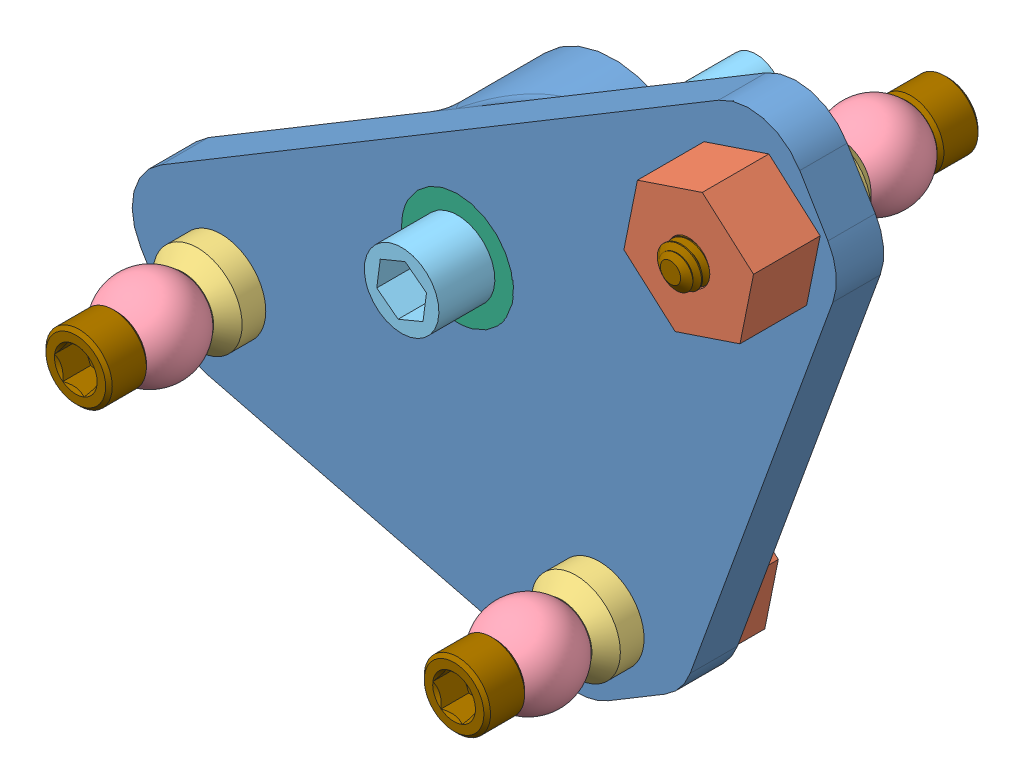
SolidWorks assembly Bell_Crank_Asm, configuration Default. Lengths in mm.
Overall size (48.74 42.1 23.91).
18 component instances, 9 part files, 34 mates.
Components (placement in the parent):
- Bell_Crank-1: Bell_Crank [Default] at (6.8967 -52.6546 -14.6326) x (-0.857289 -0.514836 0) z (0 0 -1) size (42.81 23.4 12.06)
- 2-56_Lock_Nut_MC-91831A002-1: 2-56_Lock_Nut_MC-91831A002 [Default] at (42.2907 -3.3681 -14.6326) size (6.95 7.19 3.57)
- 2-56_Lock_Nut_MC-91831A002-2: 2-56_Lock_Nut_MC-91831A002 [Default] at (33.9367 -25.6257 -20.7444) size (6.95 7.19 3.57)
- 2-56_Lock_Nut_MC-91831A002-3: 2-56_Lock_Nut_MC-91831A002 [Default] at (13.6564 -20.5642 -20.7444) size (6.95 7.19 3.57)
- 2-56_Ball_Joint_Base-1: 2-56_Ball_Joint_Base [Default] at (33.9367 -25.6257 -14.6326) x (-1 0 0) z (0 0 1) size (4.78 4.78 2.03)
- 2-56_Ball_Joint_Base-2: 2-56_Ball_Joint_Base [Default] at (13.6564 -20.5642 -14.6326) x (-1 0 0) z (0 0 1) size (4.78 4.78 2.03)
- 2-56_Ball_Joint_Half_Sphere-1: 2-56_Ball_Joint_Half_Sphere [Default] at (33.9367 -25.6257 -10.8099) x (0.923728 0.383049 0) z (0.383049 -0.923728 0) size (4.78 3.58 4.78)
- 2-56_Ball_Joint_Half_Sphere-2: 2-56_Ball_Joint_Half_Sphere [Default] at (13.6564 -20.5642 -10.8099) x (0.923728 0.383049 0) z (0.383049 -0.923728 0) size (4.78 3.58 4.78)
- 2-56_Ball_Joint_Base-3: 2-56_Ball_Joint_Base [Default] at (42.2907 -3.3681 -17.1726) x (-0.923728 -0.383049 0) z (0 0 -1) size (4.78 4.78 2.03)
- 2-56_Ball_Joint_Half_Sphere-3: 2-56_Ball_Joint_Half_Sphere [Default] at (42.2907 -3.3681 -20.9953) x (-0.049233 0.998787 0) z (-0.998787 -0.049233 0) size (4.78 3.58 4.78)
- 3.0mm_x_16mm_Screw_MC-91292A115-1: 3.0mm_x_16mm_Screw_MC-91292A115 [Default] at (26.3273 -12.9548 -11.6326) x (-0.923728 -0.383049 0) z (0 0 -1) size (4 4 19)
- 3.0mm_x_6.0mm_x_2.5mm_Ball_Bearing-1: 3.0mm_x_6.0mm_x_2.5mm_Ball_Bearing [Default] at (26.3273 -12.9548 -20.4892) x (0.923728 0.383049 0) z (0 0 -1) size (6 6 2.5)
- 3.0mm_x_6.0mm_x_2.5mm_Ball_Bearing-2: 3.0mm_x_6.0mm_x_2.5mm_Ball_Bearing [Default] at (26.3273 -12.9548 -14.6326) x (0.923728 0.383049 0) z (0 0 -1) size (6 6 2.5)
- 3mm_x_1mm_Spacer-1: 3mm_x_1mm_Spacer [Default] at (26.3273 -12.9548 -24.0052) size (4 4 1.02)
- 3mm_x_015in_spacer-1: 3mm_x_015in_spacer [Default] at (26.3273 -12.9548 -20.9426) size (4 4 3.81)
- 2-56_0.5in_Allen_Head_Cap_Screw_2_MC-92196A081-1: 2-56_0.5in_Allen_Head_Cap_Screw_2_MC-92196A081 [92196A081] at (33.9367 -25.6257 -21.7192) x (-0.923728 -0.383049 0) z (0 0 -1) size (3.56 3.56 15.4)
- 2-56_0.5in_Allen_Head_Cap_Screw_2_MC-92196A081-2: 2-56_0.5in_Allen_Head_Cap_Screw_2_MC-92196A081 [92196A081] at (13.6564 -20.5642 -21.7192) x (-0.923728 -0.383049 0) z (0 0 -1) size (3.56 3.56 15.4)
- 2-56_0.5in_Allen_Head_Cap_Screw_2_MC-92196A081-3: 2-56_0.5in_Allen_Head_Cap_Screw_2_MC-92196A081 [92196A081] at (42.2907 -3.3681 -10.086) size (3.56 3.56 15.4)
Mates (geometry in assembly coordinates):
- Coincident1: coincident anti-aligned: axis of 3.0mm_x_6.0mm_x_2.5mm_Ball_Bearing-2 through (26.3273 -12.9548 -17.1326) axis (0 0 1); axis of Bell_Crank-1 through (26.3273 -12.9548 -20.3476) axis (0 0 -1)
- Distance1: distance = 0 mm aligned: plane of Bell_Crank-1 through (7.7008 -18.2151 -14.6326) normal (0 0 1); plane of 3.0mm_x_6.0mm_x_2.5mm_Ball_Bearing-2 through (26.3273 -12.9548 -14.6326) normal (0 0 1)
- Coincident3: coincident anti-aligned: axis of 3.0mm_x_6.0mm_x_2.5mm_Ball_Bearing-1 through (26.3273 -12.9548 -22.9892) axis (0 0 1); axis of Bell_Crank-1 through (26.3273 -12.9548 -20.3476) axis (0 0 -1)
- Distance2: distance = 0 mm aligned: plane of 3.0mm_x_6.0mm_x_2.5mm_Ball_Bearing-1 through (26.3273 -12.9548 -22.9892) normal (0 0 -1); plane of Bell_Crank-1 through (26.3273 -12.9548 -22.9892) normal (0 0 -1)
- Coincident7: coincident aligned: axis of Bell_Crank-1 through (33.9367 -25.6257 -14.6326) axis (0 0 -1); axis of 2-56_Ball_Joint_Base-1 through (33.9367 -25.6257 -13.3626) axis (0 0 -1)
- Distance5: distance = 0 mm anti-aligned: plane of Bell_Crank-1 through (7.7008 -18.2151 -14.6326) normal (0 0 1); plane of 2-56_Ball_Joint_Base-1 through (33.9367 -25.6257 -14.6326) normal (0 0 -1)
- Coincident9: coincident anti-aligned: axis of 2-56_Ball_Joint_Base-1 through (33.9367 -25.6257 -13.3626) axis (0 0 -1); axis of 2-56_Ball_Joint_Half_Sphere-1 through (33.9367 -25.6257 -12.3387) axis (0 0 1)
- Distance6: distance = 0 mm anti-aligned: plane of 2-56_Ball_Joint_Base-1 through (33.9367 -25.6257 -12.6006) normal (0 0 1); plane of 2-56_Ball_Joint_Half_Sphere-1 through (33.9367 -25.6257 -12.6006) normal (0 0 -1)
- Coincident11: coincident aligned: axis of Bell_Crank-1 through (13.6564 -20.5642 -14.6326) axis (0 0 -1); axis of 2-56_Ball_Joint_Base-2 through (13.6564 -20.5642 -12.6006) axis (0 0 -1)
- Distance7: distance = 0.0305 mm anti-aligned: plane of Bell_Crank-1 through (7.7008 -18.2151 -14.6326) normal (0 0 1); plane of 2-56_Ball_Joint_Base-2 through (13.6564 -20.5642 -14.6326) normal (0 0 -1)
- Coincident13: coincident anti-aligned: axis of 2-56_Ball_Joint_Base-2 through (13.6564 -20.5642 -13.3626) axis (0 0 -1); axis of 2-56_Ball_Joint_Half_Sphere-2 through (13.6564 -20.5642 -12.3387) axis (0 0 1)
- Distance8: distance = 0 mm anti-aligned: plane of 2-56_Ball_Joint_Half_Sphere-2 through (13.6564 -20.5642 -12.6006) normal (0 0 -1); plane of 2-56_Ball_Joint_Base-2 through (13.6564 -20.5642 -12.6006) normal (0 0 1)
- Coincident16: coincident anti-aligned: axis of 2-56_Ball_Joint_Base-3 through (42.2907 -3.3681 -18.4426) axis (0 0 1); axis of Bell_Crank-1 through (42.2907 -3.3681 -14.6326) axis (0 0 -1)
- Coincident19: coincident anti-aligned: plane of 2-56_Ball_Joint_Base-3 through (42.2907 -3.3681 -17.1726) normal (0 0 1); plane of Bell_Crank-1 through (7.7008 -18.2151 -17.1726) normal (0 0 -1)
- Coincident18: coincident anti-aligned: axis of 2-56_Ball_Joint_Base-3 through (42.2907 -3.3681 -19.2046) axis (0 0 1); axis of 2-56_Ball_Joint_Half_Sphere-3 through (42.2907 -3.3681 -19.4665) axis (0 0 -1)
- Distance10: distance = 0 mm anti-aligned: plane of 2-56_Ball_Joint_Half_Sphere-3 through (42.2907 -3.3681 -19.2046) normal (0 0 1); plane of 2-56_Ball_Joint_Base-3 through (42.2907 -3.3681 -19.2046) normal (0 0 -1)
- Coincident20: coincident anti-aligned: plane of 3.0mm_x_6.0mm_x_2.5mm_Ball_Bearing-1 through (26.3273 -12.9548 -22.9892) normal (0 0 -1); plane of 3mm_x_1mm_Spacer-1 through (26.3273 -12.9548 -22.9892) normal (0 0 1)
- Coincident22: coincident anti-aligned: plane of 3.0mm_x_6.0mm_x_2.5mm_Ball_Bearing-2 through (26.3273 -12.9548 -17.1326) normal (0 0 -1); plane of 3mm_x_015in_spacer-1 through (26.3273 -12.9548 -17.1326) normal (0 0 1)
- Coincident31: coincident anti-aligned: plane of Bell_Crank-1 through (7.7008 -18.2151 -14.6326) normal (0 0 1); plane of 2-56_Lock_Nut_MC-91831A002-1 through (45.766 -2.2006 -14.6326) normal (0 0 -1)
- Coincident34: coincident anti-aligned: plane of Bell_Crank-1 through (7.7008 -18.2151 -17.1726) normal (0 0 -1); plane of 2-56_Lock_Nut_MC-91831A002-2 through (37.412 -24.4582 -17.1726) normal (0 0 1)
- Coincident36: coincident anti-aligned: plane of Bell_Crank-1 through (7.7008 -18.2151 -17.1726) normal (0 0 -1); plane of 2-56_Lock_Nut_MC-91831A002-3 through (17.1317 -19.3966 -17.1726) normal (0 0 1)
- Coincident41: coincident anti-aligned: axis of Bell_Crank-1 through (26.3273 -12.9548 -16.9033) axis (0 0 -1); axis of 3.0mm_x_16mm_Screw_MC-91292A115-1 through (26.3273 -12.9548 -30.6326) axis (0 0 1)
- Coincident42: coincident anti-aligned: plane of 3.0mm_x_16mm_Screw_MC-91292A115-1 through (26.3273 -12.9548 -14.6326) normal (0 0 -1); plane of 3.0mm_x_6.0mm_x_2.5mm_Ball_Bearing-2 through (26.3273 -12.9548 -14.6326) normal (0 0 1)
- Coincident43: coincident anti-aligned: axis of 3.0mm_x_16mm_Screw_MC-91292A115-1 through (26.3273 -12.9548 -30.6326) axis (0 0 1); axis of 3mm_x_015in_spacer-1 through (26.3273 -12.9548 -17.1326) axis (0 0 -1)
- Coincident44: coincident anti-aligned: axis of 3.0mm_x_16mm_Screw_MC-91292A115-1 through (26.3273 -12.9548 -30.6326) axis (0 0 1); axis of 3mm_x_1mm_Spacer-1 through (26.3273 -12.9548 -22.9892) axis (0 0 -1)
- Coincident45: coincident anti-aligned: axis of 2-56_Ball_Joint_Half_Sphere-3 through (42.2907 -3.3681 -19.4665) axis (0 0 -1); axis of 2-56_0.5in_Allen_Head_Cap_Screw_2_MC-92196A081-3 through (42.2907 -3.3681 -24.7926) axis (0 0 1)
- Coincident46: coincident anti-aligned: axis of 2-56_0.5in_Allen_Head_Cap_Screw_2_MC-92196A081-2 through (13.6564 -20.5642 -7.0126) axis (0 0 -1); axis of 2-56_Ball_Joint_Half_Sphere-2 through (13.6564 -20.5642 -12.3387) axis (0 0 1)
- Coincident47: coincident anti-aligned: axis of 2-56_0.5in_Allen_Head_Cap_Screw_2_MC-92196A081-1 through (33.9367 -25.6257 -7.0126) axis (0 0 -1); axis of 2-56_Ball_Joint_Half_Sphere-1 through (33.9367 -25.6257 -12.3387) axis (0 0 1)
- Coincident48: coincident anti-aligned: plane of 2-56_Ball_Joint_Half_Sphere-3 through (42.2907 -3.3681 -22.786) normal (0 0 -1); plane of 2-56_0.5in_Allen_Head_Cap_Screw_2_MC-92196A081-3 through (42.2907 -3.3681 -22.786) normal (0 0 1)
- Coincident49: coincident anti-aligned: plane of 2-56_Ball_Joint_Half_Sphere-2 through (13.6564 -20.5642 -9.0192) normal (0 0 1); plane of 2-56_0.5in_Allen_Head_Cap_Screw_2_MC-92196A081-2 through (13.6564 -20.5642 -9.0192) normal (0 0 -1)
- Coincident50: coincident anti-aligned: plane of 2-56_Ball_Joint_Half_Sphere-1 through (33.9367 -25.6257 -9.0192) normal (0 0 1); plane of 2-56_0.5in_Allen_Head_Cap_Screw_2_MC-92196A081-1 through (33.9367 -25.6257 -9.0192) normal (0 0 -1)
- Coincident51: coincident anti-aligned: axis of 2-56_Lock_Nut_MC-91831A002-1 through (42.2907 -3.3681 -11.0607) axis (0 0 -1); axis of 2-56_0.5in_Allen_Head_Cap_Screw_2_MC-92196A081-3 through (42.2907 -3.3681 -24.7926) axis (0 0 1)
- Coincident52: coincident anti-aligned: axis of 2-56_Lock_Nut_MC-91831A002-3 through (13.6564 -20.5642 -17.1726) axis (0 0 -1); axis of 2-56_Ball_Joint_Half_Sphere-2 through (13.6564 -20.5642 -12.3387) axis (0 0 1)
- Coincident53: coincident aligned: axis of 2-56_Lock_Nut_MC-91831A002-2 through (33.9367 -25.6257 -17.1726) axis (0 0 -1); axis of 2-56_0.5in_Allen_Head_Cap_Screw_2_MC-92196A081-1 through (33.9367 -25.6257 -7.0126) axis (0 0 -1)
